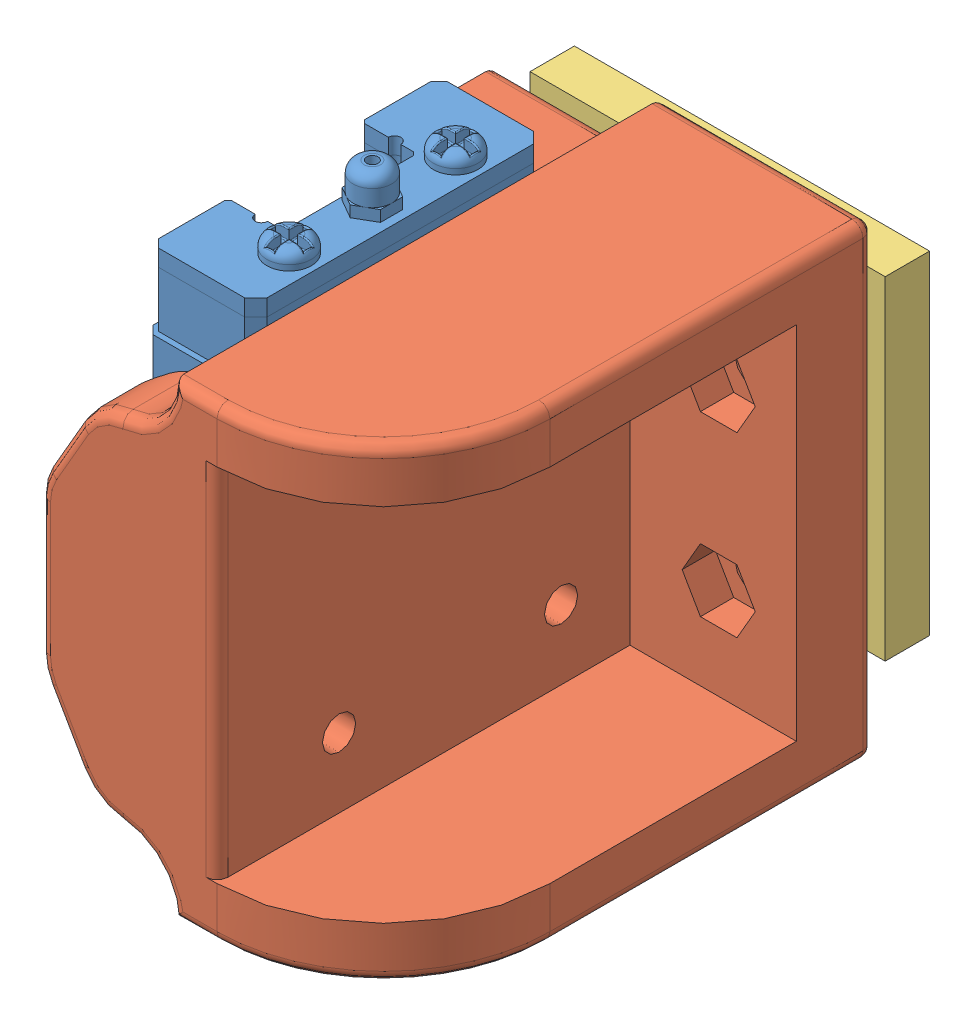
SolidWorks assembly Ползун с зажимом зеркально, configuration По умолчанию. Lengths in mm.
Overall size (34 71.49 50.2).
3 component instances, 3 part files, 11 mates.
Components (placement in the parent):
- Ползун-1: Ползун [Default] at (-13 6.5 0) x (0 0 1) z (0 1 0) size (27 10 50.47)
- Тавр-1: Тавр [По умолчанию] at (4 6.7 -18) x (0 0 1) z (-1 0 0) size (44.2 66.29 34)
- Прижимная планка 3-1: Прижимная планка 3 [По умолчанию] at (-0.7637 -0.7936 -44.6739) x (0 0 1) z (-1 0 0) size (4 30 33)
Mates (geometry in assembly coordinates):
- Совпадение1: coincident anti-aligned: plane of Ползун-1 through (-7 0 6) normal (0 -1 0); plane of assembly through (0 0 0) normal (0 1 0)
- Совпадение2: coincident aligned: plane of Ползун-1 through (0 38.9 -13.5) normal (1 0 0); plane of assembly through (0 0 0) normal (1 0 0)
- Совпадение3: coincident anti-aligned: plane of Ползун-1; plane of assembly through (0 0 0) normal (0 0 1)
- Концентричный1: concentric aligned: cylinder of Ползун-1 through (0 32.7 10) axis (1 0 0) radius 1.25; cylinder of Тавр-1 through (0 32.7 10) axis (1 0 0) radius 1.6
- Концентричный2: concentric aligned: cylinder of Ползун-1 through (0 12.7 -10) axis (1 0 0) radius 1.25; cylinder of Тавр-1 through (0 12.7 -10) axis (1 0 0) radius 1.6
- Совпадение4: coincident anti-aligned: plane of Ползун-1 through (0 38.9 -13.5) normal (1 0 0); plane of Тавр-1 through (0 6.7 -18) normal (-1 0 0)
- Параллельность1: parallel aligned: plane of Ползун-1 through (-7 45.4 6) normal (0 1 0); plane of Тавр-1 through (0 38.7 -18) normal (0 1 0)
- Концентричный4: concentric anti-aligned: cylinder of Тавр-1 through (12 30.7 -23.2) axis (0 0 1) radius 1.6; cylinder of Прижимная планка 3-1 through (12 30.7 -25.2) axis (0 0 -1) radius 1.6
- Концентричный5: concentric anti-aligned: cylinder of Тавр-1 through (-8 14.7 -23.2) axis (0 0 1) radius 1.6; cylinder of Прижимная планка 3-1 through (-8 14.7 -25.2) axis (0 0 -1) radius 1.6
- Concentric2: concentric anti-aligned: cylinder of Тавр-1 through (12 14.7 -23.2) axis (0 0 1) radius 1.6; cylinder of Прижимная планка 3-1 through (12 14.7 -25.2) axis (0 0 -1) radius 1.6
- Coincident2: coincident anti-aligned: plane of Прижимная планка 3-1 through (-0.7637 -0.7936 -25.2) normal (0 0 1); plane of assembly through (0 0 -25.2) normal (0 0 -1)
